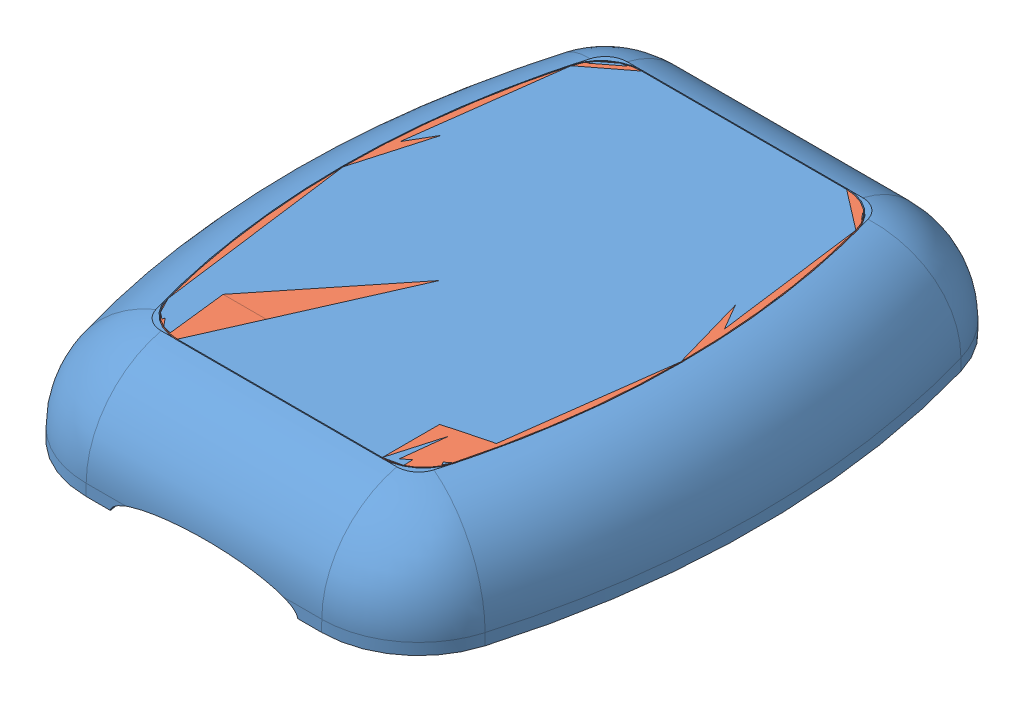
SolidWorks assembly Top_Enclosure_Assembly, configuration Default. Lengths in mm.
Overall size (62.56 20.91 77.84).
4 component instances, 4 part files, 9 mates.
Components (placement in the parent):
- Top_Enclosure_Part-1: Top_Enclosure_Part [Default] at (43.57 43.7195 67.3721) x (-1 0 0) z (0 0 1) size (62.56 20.91 77.84)
- Glass_Screen_V2.3-1: Glass_Screen_V2.3 [Default] at (43.57 43.7195 67.3721) x (-1 0 0) z (0 0 1) size (40.02 1.2 55.02)
- Rubber_Top-1: Rubber_Top [Default] at (43.57 43.7195 67.3721) x (-1 0 0) z (0 0 1) size (53.49 8.31 59.76)
- Screen-1: Screen [Default] at (43.57 51.8995 67.8721) x (0 0 1) z (-1 0 0) size (51.4 18.06 34.2)
Mates (geometry in assembly coordinates):
- Coincident17: coincident anti-aligned: plane of Top_Enclosure_Part-1 through (57.5281 54.0695 90.7721) normal (0 -1 0); plane of Screen-1 through (43.57 54.0695 67.8721) normal (0 1 0)
- Symmetric1: symmetric aligned: plane of Top_Enclosure_Part-1 through (43.57 43.7195 67.3721) normal (-1 0 0); plane of Screen-1 through (60.67 54.0695 44.9721) normal (1 0 0); plane of Screen-1 through (26.47 54.0695 44.9721) normal (-1 0 0)
- Distance5: distance = 0.1 mm: plane of Screen-1 through (60.57 54.0695 44.8721) normal (0 0 -1); line of Top_Enclosure_Part-1 through (58.5281 54.0695 44.7721) axis (1 0 0)
- Coincident62: coincident aligned: plane of Top_Enclosure_Part-1 through (43.57 43.7195 67.3721) normal (-1 0 0); plane of Rubber_Top-1 through (43.57 43.7195 67.3721) normal (-1 0 0)
- Coincident63: coincident anti-aligned: plane of Top_Enclosure_Part-1 through (43.57 51.3195 67.3721) normal (0 -1 0); plane of Rubber_Top-1 through (43.57 51.3195 67.3721) normal (0 1 0)
- Coincident65: coincident aligned: line of Top_Enclosure_Part-1 through (20.0004 48.3195 42.4721) axis (1 0 0); line of Rubber_Top-1 through (20.4026 48.3195 42.4721) axis (1 0 0)
- Coincident66: coincident anti-aligned: plane of Top_Enclosure_Part-1 through (43.57 55.2195 67.3721) normal (0 1 0); plane of Glass_Screen_V2.3-1 through (55.7119 55.2195 89.9817) normal (0 -1 0)
- Coincident67: coincident aligned: plane of Top_Enclosure_Part-1 through (43.57 43.7195 67.3721) normal (-1 0 0); plane of Glass_Screen-1 through (43.57 43.7195 67.3721) normal (-1 0 0)
- Width1: width aligned: plane of Glass_Screen_V2.3-1 through (55.7119 56.4195 39.8625) normal (0 0 -1); plane of Glass_Screen_V2.3-1 through (31.4281 56.4195 94.8817) normal (0 0 1); plane of Top_Enclosure_Part-1 through (55.7119 55.2195 39.7625) normal (0 0.008727 0.999962); plane of Top_Enclosure_Part-1 through (31.4281 55.2195 94.9817) normal (0 0.008727 -0.999962)
